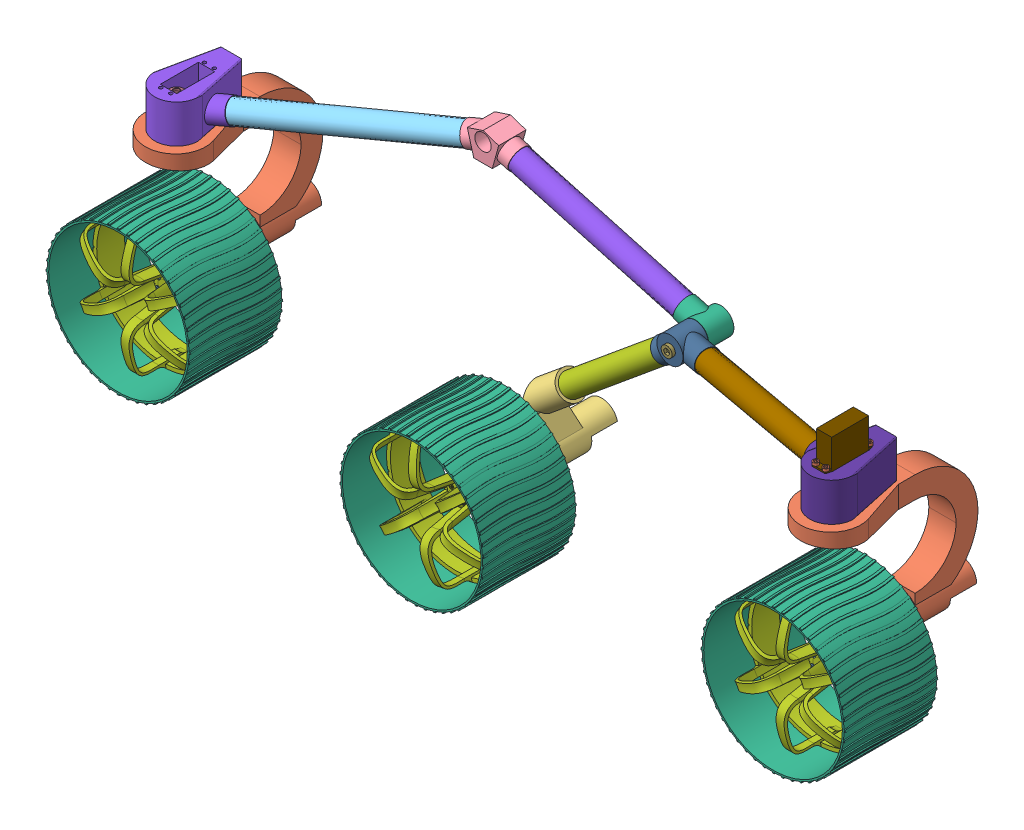
SolidWorks assembly calculation, configuration Default. Lengths in mm.
Overall size (732 280.02 208.42).
78 component instances, 30 part files, 39 mates.
Components (placement in the parent):
- Wheel + connector(left,front)-1: Wheel + connector(left,front) [Default] at (-65.0403 143.7607 -98.2826) size (132 218.24 177.42) (flexible)
  - Wheel motor-1: Wheel motor [Default] at (-237.163 -139.4989 47.5831) x (-0.888315 -0.459235 0) z (0 0 1) size (25 25 73.38)
  - Wheel connector(left,front)-1: Wheel connector(left,front) [Default] at (-249.6319 -84.5922 -11.0463) x (0 0 -1) z (1 0 0) size (150.03 127 55.1)
  - connector to wheel-1: connector to wheel [Default] at (-234.9597 -143.7607 86.2826) x (0.707107 0.707107 0) z (0 0 -1) size (25 25 12.5)
  - M3 nut-1: M3 nut [Default] at (-239.9095 -138.811 75.0326) x (-0.965926 0.258819 0) z (0 0 1) size (5 6.35 2.75)
  - M3 nut-2: M3 nut [Default] at (-239.9095 -148.7105 75.0326) x (-0.707107 0.707107 0) z (0 0 1) size (5 6.35 2.75)
  - M3 nut-3: M3 nut [Default] at (-230.01 -138.811 75.0326) x (-0.707107 0.707107 0) z (0 0 1) size (5 6.35 2.75)
  - M3 nut-4: M3 nut [Default] at (-230.01 -148.7105 75.0326) x (-0.258819 0.965926 0) z (0 0 1) size (5 6.35 2.75)
  - M3 bolt for wheels-1: M3 bolt for wheels [Default] at (-239.9095 -148.7105 97.5326) x (-0.923728 -0.383049 0) z (0 0 -1) size (5 5 25.25)
  - M3 bolt for wheels-2: M3 bolt for wheels [Default] at (-230.01 -148.7105 97.5326) x (-0.923728 -0.383049 0) z (0 0 -1) size (5 5 25.25)
  - M3 bolt for wheels-3: M3 bolt for wheels [Default] at (-230.01 -138.811 97.5326) x (-0.923728 -0.383049 0) z (0 0 -1) size (5 5 25.25)
  - M3 bolt for wheels-4: M3 bolt for wheels [Default] at (-239.9095 -138.811 97.5326) x (-0.923728 -0.383049 0) z (0 0 -1) size (5 5 25.25)
  - Wheel-1: Wheel [Default] at (-234.9597 -143.7607 98.2826) x (-1 0 0) z (0 0 1) size (132 132 85)
    - Wheel Part-1-1: Wheel Part-1 [Default] at origin size (132 132 85)
    - Wheel Part-2-1: Wheel Part-2 [Default] at (0 0 -2) size (127 128.13 59.75)
  - Steering connector(left,front)-1: Steering connector(left,front) [Default] at (-237.0258 -27.059 85.0059) x (0 0 -1) z (1 0 0) size (70 36.07 55.83)
  - Washer(M6)-1: Washer(M6) [Default] at (-237.0258 -27.559 85.0059) size (8.76 0.5 8.76)
  - double row cylindrical roller bearing_is-1: double row cylindrical roller bearing_is [IS 6458 DC - 49-6-S] at (-237.0258 -22.059 85.0059) x (0.999846 0 -0.017538) z (0 -1 0) size (15 15 10)
  - Steering thor joint-1: Steering thor joint [Default] at (-211.1744 -19.7982 66.0789) x (-0.019989 0 -0.9998) z (0 1 0) size (14.13 14.13 58.56)
    - bolt head-1: bolt head [Default] at (-18.4031 26.2188 19.7392) size (14 14 8)
    - Bogie bolt-1: Bogie bolt [Default] at (-18.4064 26.2246 14.7392) x (-1 0 0) z (0 0 -1) size (9 10.39 55.56)
    - Bolt servo connector-1: Bolt servo connector [Default] at (-18.4031 26.2188 19.7392) x (0.99996 0.008969 0) z (0 0 1) size (14 14 3)
- Wheel + motor for centre-1: Wheel + motor for centre [Default] at (0 0 31) size (154.09 154.09 127.88) (flexible)
  - Wheel motor(RH)-1: Wheel motor(RH) [Default] at (0 -4.7975 -50.6995) size (25 25 73.38)
  - connector to wheel(RH)-1: connector to wheel(RH) [Default] at (0 0 -12) x (0.564451 0.825467 0) z (0 0 -1) size (25 25 12.5)
  - M3 bolt for wheels(RH)-1: M3 bolt for wheels(RH) [Default] at (3.9512 5.7783 -0.75) x (-0.928426 -0.371518 0) z (0 0 -1) size (5 5 25.25)
  - M3 bolt for wheels(RH)-2: M3 bolt for wheels(RH) [Default] at (5.7783 -3.9512 -0.75) x (-0.969147 0.246485 0) z (0 0 -1) size (5 5 25.25)
  - M3 bolt for wheels(RH)-3: M3 bolt for wheels(RH) [Default] at (-3.9512 -5.7783 -0.75) x (0.480752 -0.876857 0) z (0 0 -1) size (5 5 25.25)
  - M3 bolt for wheels(RH)-4: M3 bolt for wheels(RH) [Default] at (-5.7783 3.9512 -0.75) x (0.142845 -0.989745 0) z (0 0 -1) size (5 5 25.25)
  - M3 nut-1: M3 nut [Default] at (5.7783 -3.9512 -23.25) x (0.564451 0.825467 0) z (0 0 1) size (5 6.35 2.75)
  - M3 nut-2: M3 nut [Default] at (3.9512 5.7783 -23.25) x (0.076095 0.997101 0) z (0 0 1) size (5 6.35 2.75)
  - M3 nut-3: M3 nut [Default] at (-5.7783 3.9512 -23.25) x (-0.43265 0.901562 0) z (0 0 1) size (5 6.35 2.75)
  - M3 nut-4: M3 nut [Default] at (-3.9512 -5.7783 -23.25) x (-0.076095 -0.997101 0) z (0 0 1) size (5 6.35 2.75)
  - Wheel-1: Wheel [Default] x (-0.98282 -0.184566 0) z (0 0 1) size (132 132 85) (flexible)
    - Wheel Part-1-1: Wheel Part-1 [Default] at origin size (132 132 85)
    - Wheel Part-2-1: Wheel Part-2 [Default] at (0 0 -2) size (127 128.13 59.75)
- Wheel + connector(left,back)-1: Wheel + connector(left,back) [Default] at (534.9597 143.7607 -98.2826) size (132 244.7 177.42) (flexible)
  - Wheel motor-1: Wheel motor [Default] at (-237.163 -139.4989 47.5831) x (-0.888315 -0.459235 0) z (0 0 1) size (25 25 73.38)
  - Wheel connector(left,front)-1: Wheel connector(left,front) [Default] at (-249.6319 -84.5922 -11.0463) x (0 0 -1) z (1 0 0) size (150.03 127 55.1)
  - connector to wheel-1: connector to wheel [Default] at (-234.9597 -143.7607 86.2826) x (0.707107 0.707107 0) z (0 0 -1) size (25 25 12.5)
  - M3 nut-1: M3 nut [Default] at (-239.9095 -138.811 75.0326) x (-0.965926 0.258819 0) z (0 0 1) size (5 6.35 2.75)
  - M3 nut-2: M3 nut [Default] at (-239.9095 -148.7105 75.0326) x (-0.707107 0.707107 0) z (0 0 1) size (5 6.35 2.75)
  - M3 nut-3: M3 nut [Default] at (-230.01 -138.811 75.0326) x (-0.707107 0.707107 0) z (0 0 1) size (5 6.35 2.75)
  - M3 nut-4: M3 nut [Default] at (-230.01 -148.7105 75.0326) x (-0.258819 0.965926 0) z (0 0 1) size (5 6.35 2.75)
  - M3 bolt for wheels-1: M3 bolt for wheels [Default] at (-239.9095 -148.7105 97.5326) x (-0.923728 -0.383049 0) z (0 0 -1) size (5 5 25.25)
  - M3 bolt for wheels-2: M3 bolt for wheels [Default] at (-230.01 -148.7105 97.5326) x (-0.923728 -0.383049 0) z (0 0 -1) size (5 5 25.25)
  - M3 bolt for wheels-3: M3 bolt for wheels [Default] at (-230.01 -138.811 97.5326) x (-0.923728 -0.383049 0) z (0 0 -1) size (5 5 25.25)
  - M3 bolt for wheels-4: M3 bolt for wheels [Default] at (-239.9095 -138.811 97.5326) x (-0.923728 -0.383049 0) z (0 0 -1) size (5 5 25.25)
  - Wheel-1: Wheel [Default] at (-234.9597 -143.7607 98.2826) x (-1 0 0) z (0 0 1) size (132 132 85)
    - Wheel Part-1-1: Wheel Part-1 [Default] at origin size (132 132 85)
    - Wheel Part-2-1: Wheel Part-2 [Default] at (0 0 -2) size (127 128.13 59.75)
  - Washer(M6)-1: Washer(M6) [Default] at (-237.0258 -27.559 85.0059) size (8.76 0.5 8.76)
  - double row cylindrical roller bearing_is-1: double row cylindrical roller bearing_is [IS 6458 DC - 49-6-S] at (-237.0258 -22.059 85.0059) x (0.999846 0 -0.017538) z (0 -1 0) size (15 15 10)
  - Steering thor joint-1: Steering thor joint [Default] at (-267.2459 -18.7982 95.6489) x (-0.269974 0 0.962867) z (0 1 0) size (14.13 14.13 58.56)
    - bolt head-1: bolt head [Default] at (-18.4031 26.2188 19.7392) size (14 14 8)
    - Bogie bolt-1: Bogie bolt [Default] at (-18.4064 26.2246 14.7392) x (-1 0 0) z (0 0 -1) size (9 10.39 55.56)
    - Bolt servo connector-1: Bolt servo connector [Default] at (-18.4031 26.2188 19.7392) x (0.99996 0.008969 0) z (0 0 1) size (14 14 3)
  - Steering connector(left,back)-1: Steering connector(left,back) [LH] at (-182.0266 -27.059 84.7092) x (-0.005393 0 -0.999985) z (0.999985 0 -0.005393) size (70 36.07 51.58)
  - Servo Assembly-1: Servo Assembly [Default] at (-237.0798 4.941 75.006) x (0.999985 0 -0.005393) z (0.005393 0 0.999985) size (15.91 35.17 46.83) (flexible)
    - Servo motor-1: Servo motor [Default] at origin size (14 30 44)
    - servo shaft-1: servo shaft [Default] at (0 -3 10) x (-0.139158 0 -0.99027) z (0.99027 0 -0.139158) size (5 18 5)
    - M3 bolt-1: M3 bolt [Default] at (-4.55 5.75 20.01) x (0.867285 0 0.497812) z (0 -1 0) size (5 5 12.17)
    - M3 bolt-2: M3 bolt [Default] at (4.55 5.75 20.01) x (0.489895 0 0.871781) z (0 -1 0) size (5 5 12.17)
    - M3 bolt-3: M3 bolt [Default] at (4.55 5.75 -20.01) x (0.489895 0 0.871781) z (0 -1 0) size (5 5 12.17)
    - M3 bolt-4: M3 bolt [Default] at (-4.55 5.75 -20.01) x (0.489895 0 0.871781) z (0 -1 0) size (5 5 12.17)
- Centre wheel connector-1: Centre wheel connector [Default] at (0 -4.7299 -54.5279) x (0.967767 0.251846 0) z (0 0 1) size (52.35 77.57 100)
- Middle connector-1: Middle connector [Default] at (-73.7917 193.9512 -65.6415) size (50.33 28.64 25.44)
- Pipe 1-1: Pipe 1 [Default] at (-90.859 186.0379 -76.7876) x (0.159296 -0.908749 -0.385745) z (-0.938775 -0.260345 0.225657) size (20 20 200)
- rocker to bogie connector1-1: rocker to bogie connector1 [Default] at (120.0958 137.2554 -77.9573) x (-0.96363 0.267238 0) z (0 0 -1) size (34 24 23.18)
- Pipe 4-1: Pipe 4 [Default] at (13.5023 49.115 -54.5279) x (0.364688 -0.44104 -0.820053) z (0.77066 0.637246 0) size (20 20 122)
- Pipe 2-1: Pipe 2 [Default] at (-58.3699 186.7484 -77.9573) x (-0.190346 -0.686365 -0.701906) z (0.96363 -0.267238 0) size (20 20 170)
- Pipe 3-1: Pipe 3 [Default] at (140.1504 137.1108 -52.5148) x (0.109825 -0.748944 -0.653469) z (0.984782 -0.007103 0.173648) size (20 20 140)
- rocker to bogie connector 2-3: rocker to bogie connector 2 [LH] at (120.0958 137.2554 -77.7079) x (-0.942135 -0.335234 0) z (0 0 -1) size (52.64 30.77 24.99)
- double row cylindrical roller bearing_is-1: double row cylindrical roller bearing_is [IS 6458 DC - 49-6-S] at (120.0958 137.2554 -71.3673) size (15 15 10)
- Washer(M6)-1: Washer(M6) [Default] at (120.0958 137.2554 -66.3673) x (0.999676 -0.025465 0) z (-0.025465 -0.999676 0) size (8.76 0.5 8.76)
- double row cylindrical roller bearing_is-2: double row cylindrical roller bearing_is [IS 6458 DC - 49-6-S] at (120.0958 137.2554 -61.1179) x (0.809029 -0.587768 0) z (0 0 1) size (15 15 10)
- M5 nut-1: M5 nut [Default] at (120.0999 137.2571 -91.6306) size (8.33 10.58 5.06)
- M5 bolt for rocker to bogie-1: M5 bolt for rocker to bogie [Default] at (120.0958 137.2554 -41.4379) x (-0.923728 -0.383049 0) z (0 0 -1) size (10 10 54.33)
Mates (geometry in assembly coordinates):
- Coincident6: coincident: plane of Wheel + motor for centre-1 through (0 0 31) normal (1 0 0); plane of assembly through (0 0 0) normal (1 0 0)
- Distance2: distance = 31 mm: plane of assembly through (0 0 0) normal (0 0 1); plane of Wheel + motor for centre-1 through (0 0 31) normal (0 0 1)
- Coincident8: coincident: plane of Wheel + connector(left,front)-1/Wheel-1/Wheel Part-1-1 through (-300 0 0) normal (0 -1 0); plane of Wheel + motor for centre-1 through (0 0 31) normal (0 1 0)
- Coincident9: coincident: plane of Wheel + connector(left,front)-1/Wheel-1/Wheel Part-1-1 through (-300 0 0) normal (0 -1 0); plane of assembly through (0 0 0) normal (0 1 0)
- Coincident10: coincident: plane of Wheel + connector(left,front)-1/Wheel-1/Wheel Part-1-1 through (-300 0 0) normal (0 0 1); plane of assembly through (0 0 0) normal (0 0 1)
- Distance3: distance = 300 mm: plane of assembly through (0 0 0) normal (1 0 0); plane of Wheel + connector(left,front)-1/Wheel-1/Wheel Part-1-1 through (-300 0 0) normal (-1 0 0)
- Coincident11: coincident: plane of Wheel + connector(left,back)-1/Wheel-1/Wheel Part-1-1 through (300 0 0) normal (0 0 1); plane of assembly through (0 0 0) normal (0 0 1)
- Distance4: distance = 300 mm: plane of Wheel + connector(left,back)-1/Wheel-1/Wheel Part-1-1 through (300 0 0) normal (-1 0 0); plane of assembly through (0 0 0) normal (1 0 0)
- Coincident13: coincident: plane of Wheel + connector(left,back)-1/Wheel-1/Wheel Part-1-1 through (300 0 0) normal (0 -1 0); plane of assembly through (0 0 0) normal (0 1 0)
- Concentric1: concentric: cylinder of Wheel + motor for centre-1/Wheel motor(RH)-1 through (0 -4.7299 -5.5279) axis (0 0 -1) radius 12.5004; cylinder of Centre wheel connector-1 through (0 -4.7299 -100.5279) axis (0 0 1) radius 15
- Coincident14: coincident: plane of Wheel + motor for centre-1/Wheel motor(RH)-1 through (0 -4.7299 -5.5279) normal (0 0 1); plane of Centre wheel connector-1 through (0 -4.7299 -5.5279) normal (0 0 -1)
- Parallel7: parallel: plane of Wheel + connector(left,front)-1/Steering connector(left,front)-1 through (-312.0661 151.7017 -63.2767) normal (0 0 -1); plane of assembly through (0 0 0) normal (0 0 1)
- Parallel9: parallel: plane of Wheel + connector(left,front)-1/Wheel connector(left,front)-1 through (-314.6722 59.1685 -109.3289) normal (-1 0 0); plane of assembly through (0 0 0) normal (1 0 0)
- Parallel10: parallel: plane of Wheel + connector(left,back)-1/Wheel connector(left,front)-1 through (285.3278 59.1685 -109.3289) normal (-1 0 0); plane of assembly through (0 0 0) normal (1 0 0)
- Parallel12: parallel: plane of Wheel + connector(left,front)-1/Steering connector(left,front)-1 through (-302.0661 151.7017 -13.2767) normal (0 1 0); plane of Middle connector-1 through (-82.2868 177 -90.6415) normal (0 -1 0)
- Coincident16: coincident: axis of Middle connector-1 through (-82.9432 188.2331 -78.6903) axis (-0.938775 -0.260345 0.225657); axis of Pipe 1-1 through (-278.6141 133.9688 -31.6562) axis (0.938775 0.260345 -0.225657)
- Parallel13: parallel: plane of Wheel + connector(left,front)-1/Wheel-1/Wheel Part-1-1 through (-300 0 42.5) normal (0 0 1); plane of Middle connector-1 through (-73.7917 193.9512 -65.6415) normal (0 0 1)
- Parallel14: parallel: plane of Middle connector-1 through (-73.7917 193.9512 -65.6415) normal (1 0 0); plane of assembly through (0 0 0) normal (1 0 0)
- Distance5: distance = 6 mm: plane of Pipe 1-1 through (-90.859 186.0379 -76.7876) normal (0.938775 0.260345 -0.225657); plane of Middle connector-1 through (-96.4917 184.4758 -75.4336) normal (-0.938775 -0.260345 0.225657)
- Distance6: distance = 177 mm: plane of Middle connector-1 through (-82.2868 177 -90.6415) normal (0 -1 0); plane of assembly through (0 0 0) normal (0 1 0)
- Coincident19: coincident: axis of Middle connector-1 through (-62.2916 187.836 -77.9573) axis (0.96363 -0.267238 0); axis of rocker to bogie connector1-1 through (98.896 143.1347 -77.9573) axis (0.96363 -0.267238 0)
- Coincident23: coincident: axis of Centre wheel connector-1 through (-6.3002 32.7407 -54.5279) axis (0.77066 0.637246 0); axis of Pipe 4-1 through (107.5228 126.859 -54.5279) axis (-0.77066 -0.637246 0)
- Distance9: distance = 6 mm: plane of Centre wheel connector-1 through (39.0864 27.59 -54.5279) normal (0.77066 0.637246 0); plane of Pipe 4-1 through (13.5023 49.115 -54.5279) normal (-0.77066 -0.637246 0)
- Coincident27: coincident: axis of Middle connector-1 through (-62.2916 187.836 -77.9573) axis (0.96363 -0.267238 0); axis of Pipe 2-1 through (105.4473 141.3178 -77.9573) axis (-0.96363 0.267238 0)
- Distance10: distance = 6 mm: plane of Middle connector-1 through (-52.5881 185.1449 -77.9573) normal (0.96363 -0.267238 0); plane of Pipe 2-1 through (-58.3699 186.7484 -77.9573) normal (-0.96363 0.267238 0)
- Coincident30: coincident: axis of Pipe 4-1 through (107.5228 126.859 -54.5279) axis (-0.77066 -0.637246 0); axis of rocker to bogie connector 2-3 through (103.1413 123.236 -54.5279) axis (0.77066 0.637246 0)
- Coincident31: coincident: axis of rocker to bogie connector1-1 through (120.0958 137.2554 -89.5473) axis (0 0 1); axis of rocker to bogie connector 2-3 through (120.0958 137.2554 -42.9379) axis (0 0 -1)
- Coincident33: coincident: axis of Pipe 3-1 through (278.0199 136.1164 -28.204) axis (-0.984782 0.007103 -0.173648); axis of rocker to bogie connector 2-3 through (146.0591 137.0682 -51.4729) axis (-0.984782 0.007103 -0.173648)
- Distance11: distance = 6 mm: plane of rocker to bogie connector 2-3 through (146.0591 137.0682 -51.4729) normal (0.984782 -0.007103 0.173648); plane of Pipe 3-1 through (140.1504 137.1108 -52.5148) normal (-0.984782 0.007103 -0.173648)
- Concentric2: concentric: cylinder of rocker to bogie connector1-1 through (120.0958 137.2554 -89.5473) axis (0 0 1) radius 7.5; cylinder of double row cylindrical roller bearing_is-1 through (120.0958 137.2554 -20.9757) axis (0 0 1) radius 7.5
- Coincident35: coincident: plane of rocker to bogie connector1-1 through (120.0958 137.2554 -66.3673) normal (0 0 1); plane of double row cylindrical roller bearing_is-1 through (120.0958 144.7554 -66.3673) normal (0 0 1)
- Concentric3: concentric: cylinder of double row cylindrical roller bearing_is-1 through (120.0958 137.2554 -0.5047) axis (0 0 1) radius 3; cylinder of Washer(M6)-1 through (120.0958 137.2554 -65.8673) axis (0 0 -1) radius 3
- Coincident36: coincident: plane of double row cylindrical roller bearing_is-1 through (120.0958 140.2554 -66.3673) normal (0 0 1); plane of Washer(M6)-1 through (120.0958 137.2554 -66.3673) normal (0 0 -1)
- Concentric4: concentric: cylinder of rocker to bogie connector 2-3 through (120.0958 137.2554 -56.1179) axis (0 0 -1) radius 7.5; cylinder of double row cylindrical roller bearing_is-2 through (120.0958 137.2554 -10.7263) axis (0 0 1) radius 7.5
- Coincident37: coincident: plane of rocker to bogie connector 2-3 through (120.0958 137.2554 -66.1179) normal (0 0 -1); plane of double row cylindrical roller bearing_is-2 through (124.5041 143.3231 -66.1179) normal (0 0 -1)
- Coincident38: coincident: axis of rocker to bogie connector1-1 through (120.0958 137.2554 -89.5473) axis (0 0 1); axis of M5 nut-1 through (120.0958 137.2554 -90.8978) axis (0 0 1)
- Coincident39: coincident: plane of rocker to bogie connector1-1 through (120.0958 137.2554 -89.5473) normal (0 0 -1); plane of M5 nut-1 through (120.0958 137.2554 -89.5473) normal (0 0 1)
- Coincident40: coincident: axis of rocker to bogie connector 2-3 through (120.0958 137.2554 -42.9379) axis (0 0 -1); axis of M5 bolt for rocker to bogie-1 through (120.0958 137.2554 -93.7179) axis (0 0 1)
- Coincident41: coincident: plane of rocker to bogie connector 2-3 through (120.0958 137.2554 -42.9379) normal (0 0 1); plane of M5 bolt for rocker to bogie-1 through (120.0958 137.2554 -42.9379) normal (0 0 -1)
